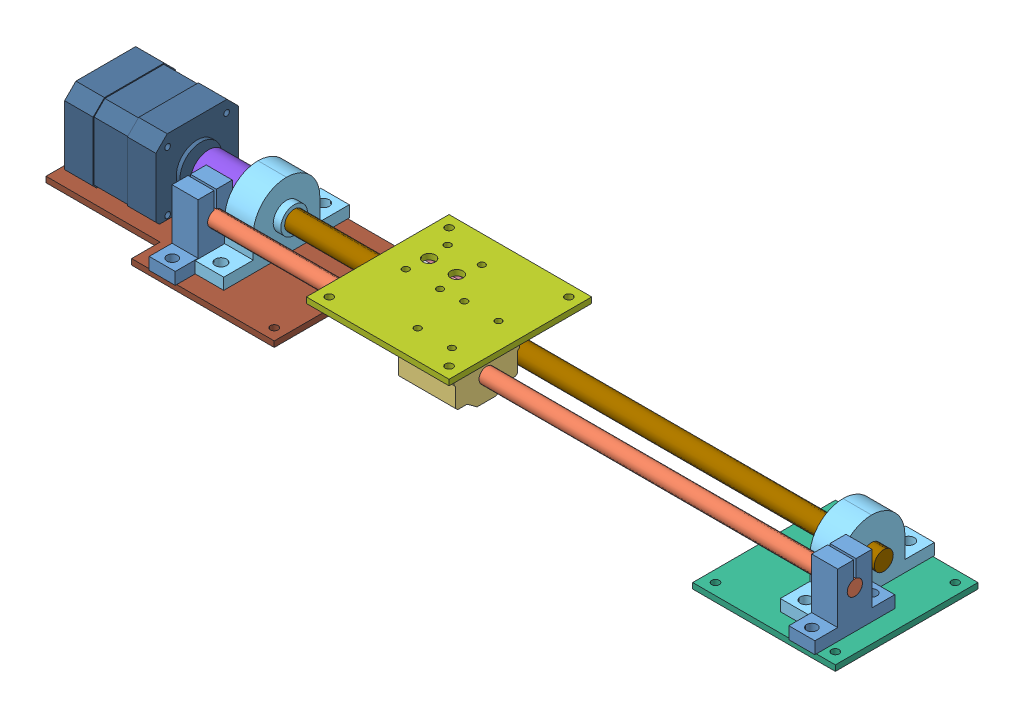
SolidWorks assembly printer, configuration Default. Lengths in mm.
Overall size (430 43.33 82.75).
14 component instances, 12 part files, 29 mates.
Components (placement in the parent):
- M8_ Mil_Tutucu-4: M8_ Mil_Tutucu [Default] at (5.5091 -3.3233 99.5698) size (13.7 33 42)
- M8_ Mil_Tutucu-5: M8_ Mil_Tutucu [Default] at (341.8091 -3.3233 99.5698) size (13.7 33 42)
- M8_300_Mil-3: M8_300_Mil [Default] at (348.6591 16.7219 99.5698) x (0 0.969737 -0.244154) z (-1 0 0) size (8 8 350)
- M8_Linear_Rulman-2: M8_Linear_Rulman [Default] at (155.0683 26.0544 99.5698) x (0 0 -1) z (-1 0 0) size (34.5 22.33 30)
- Part4^printer-1: Part4^printer [Default] at origin (virtual)
- 8mm_nut_profile-1: 8mm_nut_profile [Default] at (125.0683 14.1767 77.0698) x (0 0 1) z (-1 0 0) size (30 30 30)
- UCP_10mm-1: UCP_10mm [Default] at (327.4591 -3.3233 77.0698) x (0 0 1) z (-1 0 0) size (66 35 19)
- UCP_10mm-2: UCP_10mm [Default] at (19.8591 -3.3233 77.0698) x (0 0 -1) z (1 0 0) size (66 35 19)
- Connection_Plate_Side-1: Connection_Plate_Side [Default] at (321.1591 -6.3233 82.3198) size (75 3 75)
- Connection_Plate_Middle-1: Connection_Plate_Middle [Default] at (125.0683 29.1767 89.3198) size (75 3 75)
- Kaplin_5-10mm-1: Kaplin_5-10mm [Default] at (11.3591 14.1767 77.0698) x (0 -0.631887 -0.775061) z (0 0.775061 -0.631887) size (19 25 19)
- M10_Vidali_Mil-1: M10_Vidali_Mil [Default] at (1.3591 14.1767 77.0698) x (0 -0.999482 -0.03217) z (0 -0.03217 0.999482) size (10 340 10)
- Nema17_stepper-1: Nema17_stepper [Default] at (-67.6409 14.1767 77.0698) x (0 -1 -0.000687) z (0 -0.000687 1) size (43.3 72 43.3)
- Connection_Plate_Side_Stepper-1: Connection_Plate_Side_Stepper [Default] at (26.1591 -6.3233 82.3198) x (0 0 -1) z (1 0 0) size (75 3 135)
Mates (geometry in assembly coordinates):
- Concentric4: concentric anti-aligned: cylinder of M8_ Mil_Tutucu-5 through (348.6592 16.7219 99.5698) axis (-1 0 0) radius 4; cylinder of M8_300_Mil-3 through (-1.3409 16.7219 99.5698) axis (1 0 0) radius 4
- Concentric5: concentric anti-aligned: cylinder of M8_ Mil_Tutucu-4 through (12.3592 16.7219 99.5698) axis (-1 0 0) radius 4; cylinder of M8_300_Mil-3 through (-1.3409 16.7219 99.5698) axis (1 0 0) radius 4
- Coincident4: coincident aligned: plane of M8_ Mil_Tutucu-5 through (348.6591 3.0267 120.5698) normal (1 0 0); plane of M8_300_Mil-3 through (348.6591 16.7219 99.5698) normal (1 0 0)
- Concentric6: concentric anti-aligned: cylinder of M8_300_Mil-3 through (-1.3409 16.7219 99.5698) axis (1 0 0) radius 4; cylinder of M8_Linear_Rulman-2 through (155.0683 16.7219 99.5698) axis (-1 0 0) radius 4
- Concentric7: concentric anti-aligned: cylinder of 8mm_nut_profile-1 through (95.0683 14.1767 77.0698) axis (1 0 0) radius 4; cylinder of UCP_10mm-1 through (334.9592 14.1767 77.0698) axis (-1 0 0) radius 5
- Coincident32: coincident anti-aligned: plane of UCP_10mm-1 through (334.9591 2.6767 44.0698) normal (1 0 0); plane of M8_ Mil_Tutucu-5 through (334.9591 3.0267 120.5698) normal (-1 0 0)
- Coincident33: coincident anti-aligned: plane of M8_ Mil_Tutucu-4 through (12.3591 3.0267 120.5698) normal (1 0 0); plane of UCP_10mm-2 through (12.3591 2.6767 110.0698) normal (-1 0 0)
- Coincident34: coincident aligned: plane of M8_ Mil_Tutucu-4 through (5.5091 -3.3233 99.5698) normal (0 -1 0); plane of UCP_10mm-2 through (19.8591 -3.3233 77.0698) normal (0 -1 0)
- Concentric8: concentric aligned: cylinder of 8mm_nut_profile-1 through (95.0683 14.1767 77.0698) axis (1 0 0) radius 4; cylinder of UCP_10mm-2 through (12.3591 14.1767 77.0698) axis (1 0 0) radius 5
- Coincident35: coincident anti-aligned: plane of UCP_10mm-2 through (19.8591 -3.3233 77.0698) normal (0 -1 0); plane of Connection_Plate_Side-1 through (321.1591 -3.3233 82.3198) normal (0 1 0)
- Coincident36: coincident anti-aligned: plane of 8mm_nut_profile-1 through (95.0683 29.1767 62.0698) normal (0 1 0); plane of Connection_Plate_Middle-1 through (125.0683 29.1767 89.3198) normal (0 -1 0)
- Distance15: distance = 10 mm aligned: plane of M8_Linear_Rulman-2 through (125.0683 20.5544 116.8198) normal (0 0 1); plane of Connection_Plate_Middle-1 through (87.5683 32.1767 126.8198) normal (0 0 1)
- Concentric9: concentric anti-aligned: cylinder of UCP_10mm-2 through (12.3591 14.1767 77.0698) axis (1 0 0) radius 5; cylinder of Kaplin_5-10mm-1 through (11.3591 14.1767 77.0698) axis (-1 0 0) radius 2.5
- Concentric10: concentric anti-aligned: cylinder of Kaplin_5-10mm-1 through (1.3591 14.1767 77.0698) axis (1 0 0) radius 5; cylinder of M10_Vidali_Mil-1 through (341.3591 14.1767 77.0698) axis (-1 0 0) radius 5
- Coincident38: coincident anti-aligned: plane of Kaplin_5-10mm-1 through (1.3591 14.1767 77.0698) normal (1 0 0); plane of M10_Vidali_Mil-1 through (1.3591 14.1767 77.0698) normal (-1 0 0)
- Parallel1: parallel aligned: plane of M8_ Mil_Tutucu-4 through (-1.3409 29.6767 108.5698) normal (0 0 1); plane of 8mm_nut_profile-1 through (95.0683 29.1767 92.0698) normal (0 0 1)
- Concentric11: concentric aligned: cylinder of Kaplin_5-10mm-1 through (11.3591 14.1767 77.0698) axis (-1 0 0) radius 2.5; cylinder of Nema17_stepper-1 through (4.3591 14.1767 77.0698) axis (-1 0 0) radius 2.5
- Distance6: distance = 4 mm anti-aligned: plane of Kaplin_5-10mm-1 through (-13.6409 14.1767 77.0698) normal (-1 0 0); plane of Nema17_stepper-1 through (-17.6409 14.1767 77.0698) normal (1 0 0)
- Distance7: distance = 1 mm anti-aligned: plane of UCP_10mm-2 through (12.3591 2.6767 110.0698) normal (-1 0 0); plane of Kaplin_5-10mm-1 through (11.3591 14.1767 77.0698) normal (1 0 0)
- Distance8: distance = 1 mm anti-aligned: plane of UCP_10mm-2 through (27.3591 31.6767 94.5698) normal (0 0 1); cylinder of M8_300_Mil-3 through (-1.3409 16.7219 99.5698) axis (1 0 0) radius 4
- Coincident45: coincident aligned: plane of M8_ Mil_Tutucu-5 through (341.8091 -3.3233 99.5698) normal (0 -1 0); plane of UCP_10mm-1 through (327.4591 -3.3233 77.0698) normal (0 -1 0)
- Distance10: distance = 0.75 mm aligned: plane of UCP_10mm-1 through (319.9591 2.6767 44.0698) normal (0 0 -1); plane of Connection_Plate_Side-1 through (283.6591 -3.3233 44.8198) normal (0 0 -1)
- Distance11: distance = 0.75 mm aligned: plane of Connection_Plate_Side_Stepper-1 through (63.6591 -3.3233 44.8198) normal (0 0 -1); plane of UCP_10mm-2 through (27.3591 2.6767 44.0698) normal (0 0 -1)
- Coincident50: coincident anti-aligned: plane of UCP_10mm-2 through (19.8591 -3.3233 77.0698) normal (0 -1 0); plane of Connection_Plate_Side_Stepper-1 through (26.1591 -3.3233 82.3198) normal (0 1 0)
- Distance12: distance = 10 mm aligned: plane of M8_ Mil_Tutucu-4 through (-1.3409 3.0267 120.5698) normal (-1 0 0); plane of Connection_Plate_Side_Stepper-1 through (-11.3409 -3.3233 119.8198) normal (-1 0 0)
- Coincident52: coincident anti-aligned: plane of M8_Linear_Rulman-2 through (125.0683 26.0544 99.5698) normal (-1 0 0); plane of 8mm_nut_profile-1 through (125.0683 14.1767 77.0698) normal (1 0 0)
- Distance13: distance = 10 mm aligned: plane of M8_ Mil_Tutucu-5 through (348.6591 3.0267 120.5698) normal (1 0 0); plane of Connection_Plate_Side-1 through (358.6591 -3.3233 119.8198) normal (1 0 0)
- Distance16: distance = 7.5 mm aligned: plane of M8_Linear_Rulman-2 through (155.0683 26.0544 99.5698) normal (1 0 0); plane of Connection_Plate_Middle-1 through (162.5683 32.1767 126.8198) normal (1 0 0)
- Coincident60: coincident aligned: plane of M8_ Mil_Tutucu-4 through (-1.3409 3.0267 120.5698) normal (-1 0 0); plane of M8_300_Mil-3 through (-1.3409 16.7219 99.5698) normal (-1 0 0)
